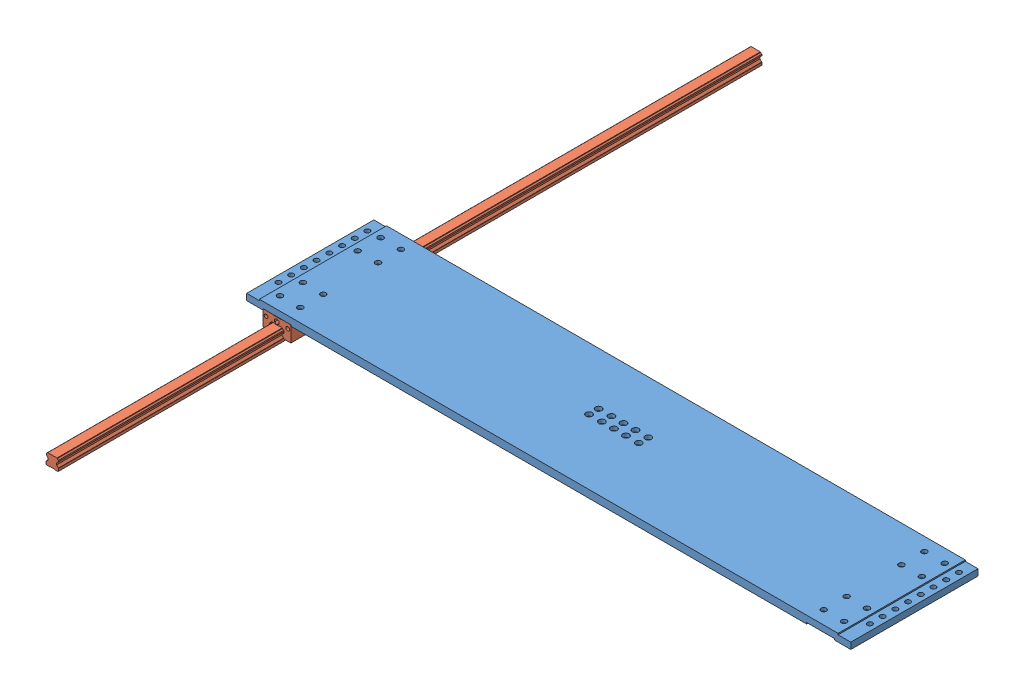
SolidWorks assembly kızakdelici, configuration Default. Lengths in mm.
Overall size (950 40 1106).
2 component instances, 2 part files, 1 mates.
Components (placement in the parent):
- alttutucu-1: alttutucu [Default] at (-58.8197 357.0959 666.4611) size (950 12 200)
- kızak2-1: kızak2 [Default] at (-261.1002 65.0413 486.4611) size (44 30 1106)
Mates (geometry in assembly coordinates):
- Coincident3: coincident anti-aligned: line of alttutucu-1; unknown of kızak2-1
